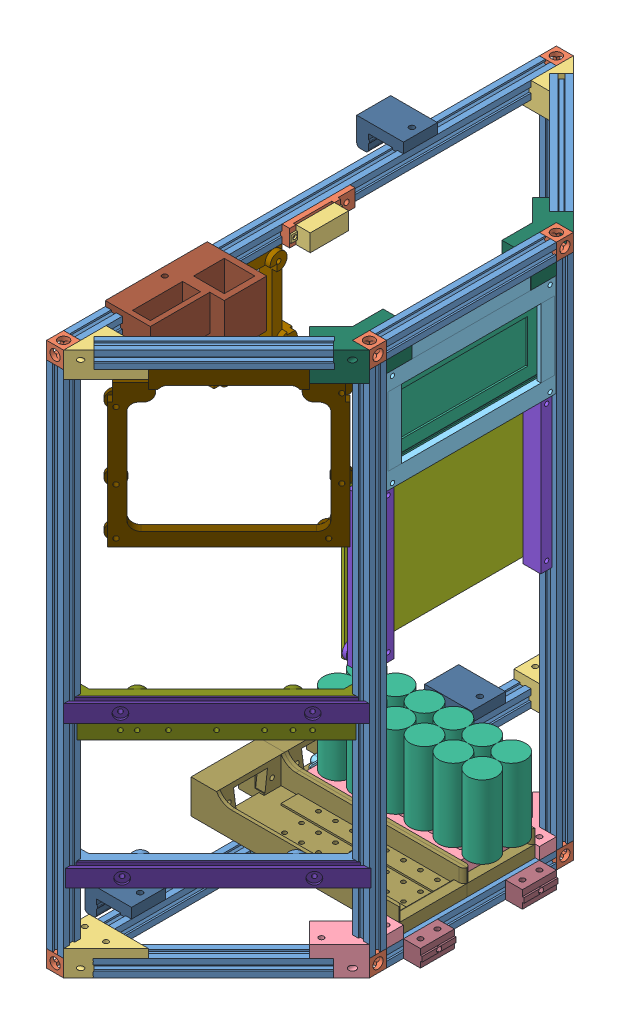
SolidWorks assembly BigRobotElectronicalBlock, configuration Default. Lengths in mm.
Overall size (127.77 326 300).
67 component instances, 24 part files, 141 mates.
Components (placement in the parent):
- Makerbeam50-1000mm-1: Makerbeam50-1000mm [280mm] at (89.8125 150.9684 79.3886) size (10 10 280)
- MakerBeam-cube-1: MakerBeam-cube [Default] at (89.8125 150.9684 359.3886) x (0 1 0) z (0 0 1) size (10 10 10)
- Makerbeam50-1000mm-2: Makerbeam50-1000mm [300mm] at (89.8125 145.9684 364.3886) x (0 0 1) z (0 -1 0) size (10 10 300)
- MakerBeam-cube-2: MakerBeam-cube [Default] at (94.8125 -159.0316 364.3886) x (0 -1 0) z (-1 0 0) size (10 10 10)
- Makerbeam50-1000mm-3: Makerbeam50-1000mm [280mm] at (89.8125 -159.0316 79.3886) size (10 10 280)
- ElectronicalMakerBeamBottomFix45-1: ElectronicalMakerBeamBottomFix45 [Right] at (94.8125 -164.0316 69.3886) x (0 0 -1) z (0 1 0) size (25 35 15)
- Makerbeam50-1000mm-5: Makerbeam50-1000mm [300mm] at (89.8125 145.9684 74.3886) x (0 0 -1) z (0 -1 0) size (10 10 300)
- MakerBeam-cube-3: MakerBeam-cube [Default] at (94.8125 -159.0316 74.3886) x (0 0 -1) z (-1 0 0) size (10 10 10)
- Makerbeam50-1000mm-6: Makerbeam50-1000mm [100mm] at (100.2145 -159.0316 81.8617) x (0.707107 0 -0.707107) z (0.707107 0 0.707107) size (10 10 100)
- MakerBeam-cube-4: MakerBeam-cube [Default] at (89.8125 150.9684 79.3886) x (-1 0 0) z (0 0 -1) size (10 10 10)
- ElectronicalMakerBeamBottomFix135-1: ElectronicalMakerBeamBottomFix135 [Right] at (94.8125 -164.0316 69.3886) x (0 0 -1) z (0 1 0) size (37.68 29.7 17)
- Makerbeam50-1000mm-7: Makerbeam50-1000mm [100mm] at (179.8125 -159.0316 169.3886) size (10 10 100)
- Makerbeam50-1000mm-8: Makerbeam50-1000mm [300mm] at (179.8125 -154.0316 164.3886) x (0 0 1) z (0 1 0) size (10 10 300)
- MakerBeam-cube-5: MakerBeam-cube [Default] at (174.8125 -159.0316 164.3886) x (0 -1 0) z (1 0 0) size (10 10 10)
- ElectronicalMakerBeamBottomFix45-2: ElectronicalMakerBeamBottomFix45 [Left] at (94.8125 155.9684 129.3886) x (0 0 1) z (0 -1 0) size (25 35 15)
- Makerbeam50-1000mm-9: Makerbeam50-1000mm [100mm] at (100.2145 150.9684 81.8617) x (0.707107 0 -0.707107) z (0.707107 0 0.707107) size (10 10 100)
- MakerBeam-cube-6: MakerBeam-cube [Default] at (179.8125 145.9684 164.3886) x (1 0 0) z (0 1 0) size (10 10 10)
- Makerbeam50-1000mm-10: Makerbeam50-1000mm [100mm] at (179.8125 150.9684 169.3886) size (10 10 100)
- MakerBeam-cube-7: MakerBeam-cube [Default] at (179.8125 150.9684 269.3886) size (10 10 10)
- Makerbeam50-1000mm-11: Makerbeam50-1000mm [300mm] at (179.8125 145.9684 274.3886) x (1 0 0) z (0 -1 0) size (10 10 300)
- MakerBeam-cube-8: MakerBeam-cube [Default] at (179.8125 -159.0316 269.3886) x (0 -1 0) z (0 0 1) size (10 10 10)
- ElectronicalMakerBeamBottomFix135-3: ElectronicalMakerBeamBottomFix135 [Left] at (204.8125 -164.0316 369.3886) x (0 0 1) z (0 1 0) size (37.68 29.7 17)
- Makerbeam50-1000mm-12: Makerbeam50-1000mm [100mm] at (170.6704 -159.0316 286.4597) x (0.707107 0 0.707107) z (-0.707107 0 0.707107) size (10 10 100)
- Makerbeam50-1000mm-13: Makerbeam50-1000mm [100mm] at (170.9252 150.9684 286.2049) x (0.707107 0 0.707107) z (-0.707107 0 0.707107) size (10 10 100)
- ElectronicalMakerBeamBottomFix45-3: ElectronicalMakerBeamBottomFix45 [Right] at (94.8125 155.9684 369.3886) x (0 0 1) z (0 -1 0) size (25 35 15)
- ElectronicalMakerBeamBottomFix45-4: ElectronicalMakerBeamBottomFix45 [Left] at (94.8125 -164.0316 309.3886) x (0 0 -1) z (0 1 0) size (25 35 15)
- 20X4LCD_SupportForBigRobot-1: 20X4LCD_SupportForBigRobot [Default] at (184.8125 78.9684 219.4386) x (-1 0 0) z (0 0 -1) size (12 69 103.9)
- 20X4LCD JHD204A-1: 20X4LCD JHD204A [Default] at (172.8125 108.7157 219.3402) x (0 -0.000058 -1) z (0 -1 0.000058) size (98 9.76 60)
- MotorBoard32_BigRobot_WithSupport-1: MotorBoard32_BigRobot_WithSupport [Default] at (277.5716 44.6572 296.8003) x (0 1 0) z (-1 0 0) size (90 121.5 15)
  - MotorBoard32-1: MotorBoard32 [Défaut] at (-10.6888 77.5617 108.2591) size (88 118.5 2)
  - MotorBoardElectronicalSupportForBigRobot-1: MotorBoardElectronicalSupportForBigRobot [Left] at (34.3112 27.4117 132.2591) x (0 1 0) z (-1 0 0) size (17.6 13 90)
  - MotorBoardElectronicalSupportForBigRobot-2: MotorBoardElectronicalSupportForBigRobot [Right] at (34.3112 127.7117 95.2591) x (0 -1 0) z (-1 0 0) size (17.6 13 90)
- UsbBoardSupport-1: UsbBoardSupport [Défaut] at (87.3125 118.9684 257.8488) x (0 -1 0) z (1 0 0) size (55 46 10.5)
- ElectronicalToMechanicalTopFixation-1: ElectronicalToMechanicalTopFixation [Default] at (81.0625 155.9684 159.3886) x (0 0 -1) z (0 1 0) size (20 27.5 16)
- PowerSwitchSupport-1: PowerSwitchSupport [Default] at (102.3125 158.9684 304.8488) x (0 0 1) z (0 -1 0) size (60 35 28)
- BatteriesBottomRackSmallRobot-1: BatteriesBottomRackSmallRobot [Default] at (121.0625 -154.0316 199.3886) x (0 0 -1) z (1 0 0) size (40 20 122.5)
- BigRobot-ElectronicalBlock-BatteriesRackSmallSupport-1: BigRobot-ElectronicalBlock-BatteriesRackSmallSupport [Default] at (164.8125 -164.0316 179.3886) x (-1 0 0) z (0 0 1) size (31 10 20)
- BigRobot-ElectronicalBlock-BatteriesRackBigSupport-1: BigRobot-ElectronicalBlock-BatteriesRackBigSupport [Default] at (104.8125 -164.0316 259.3886) x (1 0 0) z (0 0 -1) size (11 10 80)
- ElectronicalMakerBeamTopFix135-1: ElectronicalMakerBeamTopFix135 [Left] at (204.8125 155.9684 69.3886) x (0 0 -1) z (0 -1 0) size (42.68 29.7 17)
- ElectronicalMakerBeamTopFix135-2: ElectronicalMakerBeamTopFix135 [Right] at (94.8125 155.9684 369.3886) x (0 0 1) z (0 -1 0) size (42.68 29.7 17)
- BatteriesBottomRackSmallRobot-2: BatteriesBottomRackSmallRobot [Default] at (121.0625 -154.0316 239.3886) x (0 0 -1) z (1 0 0) size (40 20 122.5)
- BigRobot-ElectronicalBlock-BatteriesRackSmallSupport-2: BigRobot-ElectronicalBlock-BatteriesRackSmallSupport [Default] at (164.8125 -164.0316 239.3886) x (-1 0 0) z (0 0 1) size (31 10 20)
- BigRobotWindowCorner90x90x45degSupport_PowerboardMiddle-1: BigRobotWindowCorner90x90x45degSupport_PowerboardMiddle [Default] at (135.8125 -35.4689 320.3886) x (0 0 -1) z (0 -1 0) size (92 92 22.5)
- BigRobotWindowCorner90x90x45degCover-1: BigRobotWindowCorner90x90x45degCover [Default] at (139.8125 -29.2189 324.3886) x (0 0 -1) z (0 -1 0) size (90 90 10)
- ElectronicalMainBoard-Support-1: ElectronicalMainBoard-Support [Défaut] at (143.4467 98.9684 320.7544) x (0.707107 0 -0.707107) z (-0.707107 0 -0.707107) size (104 95.5 12.5)
- BigRobotWindowCorner90x90x45degSupport-1: BigRobotWindowCorner90x90x45degSupport [Default] at (136.3125 -113.1971 319.8886) x (0 0 -1) z (0 -1 0) size (93 93 10)
- BigRobotWindowCorner90x90x45degCover-2: BigRobotWindowCorner90x90x45degCover [Default] at (140.3125 -113.1971 323.8886) x (0 0 -1) z (0 -1 0) size (90 90 10)
- ElectronicalToMechanicalTopFixation-2: ElectronicalToMechanicalTopFixation [Default] at (81.0625 -154.0316 119.3886) x (0 0 -1) z (0 1 0) size (20 27.5 16)
- ElectronicalToMechanicalTopFixation-3: ElectronicalToMechanicalTopFixation [Default] at (81.0625 -154.0316 319.3886) x (0 0 -1) z (0 1 0) size (20 27.5 16)
- LCD_MiniVoltmeterSupport-1: LCD_MiniVoltmeterSupport [Default] at (97.8125 145.9684 200.8488) x (0 0 1) z (-1 0 0) size (40 10 5.5)
- LCD_MiniVoltmeter-1: LCD_MiniVoltmeter [Default] at (99.3125 150.9684 225.8488) x (0 0 -1) z (1 0 0) size (30.25 10.15 8.4)
- Battery-With-Support_Assembly-1: Battery-With-Support_Assembly [Default] at (202.4217 -184.624 172.3178) x (0 0 1) z (-1 0 0) size (35.62 54.25 108.57)
  - BatteriesBottomSupportComplete-1: BatteriesBottomSupportComplete [Default] at (27.3209 40.5925 25.7492) size (35.5 35 91)
  - DSub-25-Harting-1: DSub-25-Harting [По умолчанию] at (27.3159 40.5925 116.7492) size (30.8 12.5 18.9)
  - Battery-Pack2x6-1: Battery-Pack2x6 [Défaut] at (29.2673 24.0925 94.2205) x (1 0 0) z (0 1 0) size (34 102 43)
    - Batterie-Element-1: Batterie-Element [Défaut] at (5.6828 -14.1168 21.5) size (17 17 43)
    - Batterie-Element-2: Batterie-Element [Défaut] at (-11.3172 -14.1168 21.5) size (17 17 43)
    - Batterie-Element-3: Batterie-Element [Défaut] at (5.6828 2.8832 21.5) size (17 17 43)
    - Batterie-Element-4: Batterie-Element [Défaut] at (5.6828 19.8832 21.5) size (17 17 43)
    - Batterie-Element-5: Batterie-Element [Défaut] at (5.6828 36.8832 21.5) size (17 17 43)
    - Batterie-Element-6: Batterie-Element [Défaut] at (5.6828 53.8832 21.5) size (17 17 43)
    - Batterie-Element-7: Batterie-Element [Défaut] at (5.6828 70.8832 21.5) size (17 17 43)
    - Batterie-Element-8: Batterie-Element [Défaut] at (-11.3172 2.8832 21.5) size (17 17 43)
    - Batterie-Element-9: Batterie-Element [Défaut] at (-11.3172 19.8832 21.5) size (17 17 43)
    - Batterie-Element-10: Batterie-Element [Défaut] at (-11.3172 36.8832 21.5) size (17 17 43)
    - Batterie-Element-11: Batterie-Element [Défaut] at (-11.3172 53.8832 21.5) size (17 17 43)
    - Batterie-Element-12: Batterie-Element [Défaut] at (-11.3172 70.8832 21.5) size (17 17 43)
Mates (geometry in assembly coordinates):
- Concentric1: concentric anti-aligned: cylinder of Makerbeam50-1000mm-1 through (89.8125 150.9684 359.3886) axis (0 0 -1) radius 1.25; cylinder of MakerBeam-cube-1 through (89.8125 150.9684 369.3886) axis (0 0 1) radius 1.25
- Coincident1: coincident aligned: plane of Makerbeam50-1000mm-1 through (94.8125 155.9684 359.3886) normal (1 0 0); plane of MakerBeam-cube-1 through (94.8125 155.9684 369.3886) normal (1 0 0)
- Coincident2: coincident anti-aligned: plane of Makerbeam50-1000mm-1 through (89.8125 150.9684 359.3886) normal (0 0 1); plane of MakerBeam-cube-1 through (89.8125 150.9684 359.3886) normal (0 0 -1)
- Concentric2: concentric aligned: cylinder of MakerBeam-cube-1 through (89.8125 155.9684 364.3886) axis (0 1 0) radius 1.25; cylinder of Makerbeam50-1000mm-2 through (89.8125 -154.0316 364.3886) axis (0 1 0) radius 1.25
- Coincident3: coincident aligned: plane of MakerBeam-cube-1 through (89.8125 150.9684 369.3886) normal (0 0 1); plane of Makerbeam50-1000mm-2 through (84.8125 -154.0316 369.3886) normal (0 0 1)
- Coincident4: coincident anti-aligned: plane of MakerBeam-cube-1 through (94.8125 145.9684 369.3886) normal (0 -1 0); plane of Makerbeam50-1000mm-2 through (89.8125 145.9684 364.3886) normal (0 1 0)
- Concentric3: concentric anti-aligned: cylinder of Makerbeam50-1000mm-2 through (89.8125 -154.0316 364.3886) axis (0 1 0) radius 1.25; cylinder of MakerBeam-cube-2 through (89.8125 -164.0316 364.3886) axis (0 -1 0) radius 1.25
- Coincident5: coincident aligned: plane of Makerbeam50-1000mm-2 through (84.8125 -154.0316 369.3886) normal (0 0 1); plane of MakerBeam-cube-2 through (84.8125 -164.0316 369.3886) normal (0 0 1)
- Coincident6: coincident anti-aligned: plane of Makerbeam50-1000mm-2 through (89.8125 -154.0316 364.3886) normal (0 -1 0); plane of MakerBeam-cube-2 through (84.8125 -154.0316 359.3886) normal (0 1 0)
- Concentric4: concentric aligned: cylinder of MakerBeam-cube-2 through (89.8125 -159.0316 359.3886) axis (0 0 -1) radius 1.25; cylinder of Makerbeam50-1000mm-3 through (89.8125 -159.0316 359.3886) axis (0 0 -1) radius 1.25
- Coincident7: coincident aligned: plane of MakerBeam-cube-2 through (94.8125 -159.0316 364.3886) normal (1 0 0); plane of Makerbeam50-1000mm-3 through (94.8125 -160.5316 359.3886) normal (1 0 0)
- Coincident8: coincident anti-aligned: plane of MakerBeam-cube-2 through (84.8125 -164.0316 359.3886) normal (0 0 -1); plane of Makerbeam50-1000mm-3 through (89.8125 -159.0316 359.3886) normal (0 0 1)
- Coincident9: coincident anti-aligned: plane of Makerbeam50-1000mm-3 through (84.8125 -154.0316 359.3886) normal (0 1 0); plane of ElectronicalMakerBeamBottomFix45-1 through (94.8125 -154.0316 69.3886) normal (0 -1 0)
- Coincident10: coincident aligned: plane of Makerbeam50-1000mm-3 through (89.8125 -159.0316 79.3886) normal (0 0 -1); plane of ElectronicalMakerBeamBottomFix45-1 through (94.8125 -149.0316 79.3886) normal (0 0 -1)
- Coincident11: coincident aligned: plane of Makerbeam50-1000mm-3 through (84.8125 -157.5316 359.3886) normal (-1 0 0); plane of ElectronicalMakerBeamBottomFix45-1 through (84.8125 -149.0316 79.3886) normal (-1 0 0)
- Coincident13: coincident anti-aligned: plane of ElectronicalMakerBeamBottomFix45-1 through (94.8125 -149.0316 69.3886) normal (-1 0 0); plane of Makerbeam50-1000mm-5 through (94.8125 -154.0316 72.8886) normal (1 0 0)
- Concentric5: concentric aligned: cylinder of Makerbeam50-1000mm-3 through (89.8125 -159.0316 359.3886) axis (0 0 -1) radius 1.25; cylinder of MakerBeam-cube-3 through (89.8125 -159.0316 69.3886) axis (0 0 -1) radius 1.25
- Coincident14: coincident anti-aligned: plane of ElectronicalMakerBeamBottomFix45-1 through (94.8125 -149.0316 69.3886) normal (-1 0 0); plane of MakerBeam-cube-3 through (94.8125 -159.0316 74.3886) normal (1 0 0)
- Coincident15: coincident anti-aligned: plane of Makerbeam50-1000mm-3 through (89.8125 -159.0316 79.3886) normal (0 0 -1); plane of MakerBeam-cube-3 through (84.8125 -154.0316 79.3886) normal (0 0 1)
- Coincident16: coincident anti-aligned: plane of Makerbeam50-1000mm-5 through (89.8125 -154.0316 74.3886) normal (0 -1 0); plane of MakerBeam-cube-3 through (84.8125 -154.0316 69.3886) normal (0 1 0)
- Concentric6: concentric aligned: cylinder of Makerbeam50-1000mm-5 through (89.8125 -154.0316 74.3886) axis (0 1 0) radius 1.25; cylinder of MakerBeam-cube-3 through (89.8125 -154.0316 74.3886) axis (0 1 0) radius 1.25
- Coincident18: coincident anti-aligned: plane of ElectronicalMakerBeamBottomFix45-1 through (96.679 -149.0316 85.3973) normal (0.707107 0 -0.707107); plane of Makerbeam50-1000mm-6 through (167.3897 -157.5316 156.1079) normal (-0.707107 0 0.707107)
- Coincident19: coincident aligned: plane of ElectronicalMakerBeamBottomFix45-1 through (94.8125 -164.0316 69.3886) normal (0 -1 0); plane of Makerbeam50-1000mm-6 through (171.9858 -164.0316 151.5118) normal (0 -1 0)
- Coincident20: coincident anti-aligned: plane of ElectronicalMakerBeamBottomFix45-1 through (103.75 -149.0316 78.3262) normal (0.707107 0 0.707107); plane of Makerbeam50-1000mm-6 through (100.2145 -159.0316 81.8617) normal (-0.707107 0 -0.707107)
- Concentric7: concentric aligned: cylinder of Makerbeam50-1000mm-1 through (89.8125 150.9684 359.3886) axis (0 0 -1) radius 1.25; cylinder of MakerBeam-cube-4 through (89.8125 150.9684 69.3886) axis (0 0 -1) radius 1.25
- Coincident22: coincident aligned: plane of Makerbeam50-1000mm-1 through (94.8125 155.9684 359.3886) normal (1 0 0); plane of MakerBeam-cube-4 through (94.8125 145.9684 69.3886) normal (1 0 0)
- Coincident23: coincident anti-aligned: plane of Makerbeam50-1000mm-1 through (89.8125 150.9684 79.3886) normal (0 0 -1); plane of MakerBeam-cube-4 through (89.8125 150.9684 79.3886) normal (0 0 1)
- Coincident25: coincident aligned: plane of Makerbeam50-1000mm-6 through (171.9858 -164.0316 151.5118) normal (0 -1 0); plane of ElectronicalMakerBeamBottomFix135-1 through (94.8125 -164.0316 69.3886) normal (0 -1 0)
- Parallel1: parallel anti-aligned: plane of Makerbeam50-1000mm-6 through (170.9252 -159.0316 152.5724) normal (0.707107 0 0.707107); plane of ElectronicalMakerBeamBottomFix135-1 through (174.2059 -164.0316 148.782) normal (-0.707107 0 -0.707107)
- Coincident27: coincident aligned: plane of Makerbeam50-1000mm-6 through (174.4607 -154.0316 149.0369) normal (0.707107 0 -0.707107); plane of ElectronicalMakerBeamBottomFix135-1 through (184.8125 -147.0316 159.3886) normal (0.707107 0 -0.707107)
- Distance2: distance = 80 mm aligned: plane of ElectronicalMakerBeamBottomFix135-1 through (174.8125 -147.0316 159.3886) normal (1 0 0); plane of Makerbeam50-1000mm-3 through (94.8125 -154.0316 359.3886) normal (1 0 0)
- Coincident30: coincident aligned: plane of ElectronicalMakerBeamBottomFix135-1 through (94.8125 -164.0316 169.3886) normal (0 0 -1); plane of Makerbeam50-1000mm-7 through (179.8125 -159.0316 169.3886) normal (0 0 -1)
- Coincident32: coincident aligned: plane of ElectronicalMakerBeamBottomFix135-1 through (184.8125 -147.0316 169.3886) normal (1 0 0); plane of Makerbeam50-1000mm-7 through (184.8125 -154.0316 269.3886) normal (1 0 0)
- Coincident33: coincident aligned: plane of ElectronicalMakerBeamBottomFix135-1 through (94.8125 -164.0316 69.3886) normal (0 -1 0); plane of Makerbeam50-1000mm-7 through (178.3125 -164.0316 269.3886) normal (0 -1 0)
- Coincident34: coincident anti-aligned: plane of ElectronicalMakerBeamBottomFix135-1 through (94.8125 -164.0316 169.3886) normal (0 0 -1); plane of Makerbeam50-1000mm-8 through (184.8125 145.9684 169.3886) normal (0 0 1)
- Coincident35: coincident aligned: plane of Makerbeam50-1000mm-7 through (184.8125 -154.0316 269.3886) normal (1 0 0); plane of Makerbeam50-1000mm-8 through (184.8125 145.9684 165.8886) normal (1 0 0)
- Concentric8: concentric anti-aligned: cylinder of Makerbeam50-1000mm-7 through (179.8125 -159.0316 269.3886) axis (0 0 -1) radius 1.25; cylinder of MakerBeam-cube-5 through (179.8125 -159.0316 169.3886) axis (0 0 1) radius 1.25
- Concentric9: concentric aligned: cylinder of Makerbeam50-1000mm-8 through (179.8125 145.9684 164.3886) axis (0 -1 0) radius 1.25; cylinder of MakerBeam-cube-5 through (179.8125 -164.0316 164.3886) axis (0 -1 0) radius 1.25
- Coincident36: coincident anti-aligned: plane of Makerbeam50-1000mm-8 through (179.8125 -154.0316 164.3886) normal (0 -1 0); plane of MakerBeam-cube-5 through (184.8125 -154.0316 169.3886) normal (0 1 0)
- Coincident38: coincident aligned: plane of Makerbeam50-1000mm-1 through (91.3125 155.9684 359.3886) normal (0 1 0); plane of ElectronicalMakerBeamBottomFix45-2 through (94.8125 155.9684 69.3886) normal (0 1 0)
- Coincident39: coincident anti-aligned: plane of Makerbeam50-1000mm-1 through (94.8125 155.9684 359.3886) normal (1 0 0); plane of ElectronicalMakerBeamBottomFix45-2 through (94.8125 140.9684 69.3886) normal (-1 0 0)
- Coincident40: coincident anti-aligned: line of MakerBeam-cube-4 through (94.8125 155.9684 69.3886) axis (0 -1 0); line of ElectronicalMakerBeamBottomFix45-2 through (94.8125 140.9684 69.3886) axis (0 1 0)
- Coincident41: coincident aligned: plane of ElectronicalMakerBeamBottomFix45-2 through (94.8125 155.9684 69.3886) normal (0 1 0); plane of Makerbeam50-1000mm-9 through (167.3897 155.9684 156.1079) normal (0 1 0)
- Coincident42: coincident anti-aligned: plane of ElectronicalMakerBeamBottomFix45-2 through (103.75 140.9684 78.3262) normal (0.707107 0 0.707107); plane of Makerbeam50-1000mm-9 through (100.2145 150.9684 81.8617) normal (-0.707107 0 -0.707107)
- Coincident43: coincident anti-aligned: plane of ElectronicalMakerBeamBottomFix45-2 through (96.679 140.9684 85.3973) normal (0.707107 0 -0.707107); plane of Makerbeam50-1000mm-9 through (167.3897 145.9684 156.1079) normal (-0.707107 0 0.707107)
- Concentric10: concentric anti-aligned: cylinder of Makerbeam50-1000mm-8 through (179.8125 145.9684 164.3886) axis (0 -1 0) radius 1.25; cylinder of MakerBeam-cube-6 through (179.8125 155.9684 164.3886) axis (0 1 0) radius 1.25
- Coincident47: coincident aligned: plane of Makerbeam50-1000mm-8 through (184.8125 145.9684 165.8886) normal (1 0 0); plane of MakerBeam-cube-6 through (184.8125 155.9684 169.3886) normal (1 0 0)
- Coincident48: coincident anti-aligned: plane of Makerbeam50-1000mm-8 through (179.8125 145.9684 164.3886) normal (0 1 0); plane of MakerBeam-cube-6 through (179.8125 145.9684 164.3886) normal (0 -1 0)
- Coincident51: coincident anti-aligned: plane of MakerBeam-cube-6 through (184.8125 155.9684 169.3886) normal (0 0 1); plane of Makerbeam50-1000mm-10 through (179.8125 150.9684 169.3886) normal (0 0 -1)
- Concentric11: concentric anti-aligned: cylinder of Makerbeam50-1000mm-10 through (179.8125 150.9684 269.3886) axis (0 0 -1) radius 1.25; cylinder of MakerBeam-cube-7 through (179.8125 150.9684 279.3886) axis (0 0 1) radius 1.25
- Coincident52: coincident aligned: plane of Makerbeam50-1000mm-10 through (184.8125 149.4684 269.3886) normal (1 0 0); plane of MakerBeam-cube-7 through (184.8125 145.9684 279.3886) normal (1 0 0)
- Coincident53: coincident anti-aligned: plane of Makerbeam50-1000mm-10 through (179.8125 150.9684 269.3886) normal (0 0 1); plane of MakerBeam-cube-7 through (179.8125 150.9684 269.3886) normal (0 0 -1)
- Concentric12: concentric anti-aligned: cylinder of MakerBeam-cube-7 through (179.8125 145.9684 274.3886) axis (0 -1 0) radius 1.25; cylinder of Makerbeam50-1000mm-11 through (179.8125 -154.0316 274.3886) axis (0 1 0) radius 1.25
- Coincident54: coincident anti-aligned: plane of MakerBeam-cube-7 through (184.8125 145.9684 279.3886) normal (0 -1 0); plane of Makerbeam50-1000mm-11 through (179.8125 145.9684 274.3886) normal (0 1 0)
- Coincident55: coincident aligned: plane of MakerBeam-cube-7 through (184.8125 145.9684 279.3886) normal (1 0 0); plane of Makerbeam50-1000mm-11 through (184.8125 -154.0316 279.3886) normal (1 0 0)
- Coincident56: coincident anti-aligned: plane of Makerbeam50-1000mm-7 through (179.8125 -159.0316 269.3886) normal (0 0 1); plane of MakerBeam-cube-8 through (179.8125 -159.0316 269.3886) normal (0 0 -1)
- Coincident57: coincident anti-aligned: plane of Makerbeam50-1000mm-11 through (179.8125 -154.0316 274.3886) normal (0 -1 0); plane of MakerBeam-cube-8 through (174.8125 -154.0316 279.3886) normal (0 1 0)
- Coincident58: coincident aligned: plane of Makerbeam50-1000mm-7 through (184.8125 -160.5316 269.3886) normal (1 0 0); plane of MakerBeam-cube-8 through (184.8125 -164.0316 279.3886) normal (1 0 0)
- Coincident59: coincident anti-aligned: plane of Makerbeam50-1000mm-7 through (174.8125 -157.5316 269.3886) normal (-1 0 0); plane of ElectronicalMakerBeamBottomFix135-3 through (174.8125 -147.0316 279.3886) normal (1 0 0)
- Coincident60: coincident aligned: plane of Makerbeam50-1000mm-7 through (178.3125 -164.0316 269.3886) normal (0 -1 0); plane of ElectronicalMakerBeamBottomFix135-3 through (94.8125 -164.0316 369.3886) normal (0 -1 0)
- Coincident61: coincident anti-aligned: plane of MakerBeam-cube-8 through (179.8125 -159.0316 279.3886) normal (0 0 1); plane of ElectronicalMakerBeamBottomFix135-3 through (184.8125 -147.0316 279.3886) normal (0 0 -1)
- Coincident62: coincident aligned: plane of ElectronicalMakerBeamBottomFix135-3 through (184.8125 -147.0316 279.3886) normal (0.707107 0 0.707107); plane of Makerbeam50-1000mm-12 through (103.4952 -154.0316 360.7059) normal (0.707107 0 0.707107)
- Coincident63: coincident aligned: plane of ElectronicalMakerBeamBottomFix135-3 through (94.8125 -164.0316 369.3886) normal (0 -1 0); plane of Makerbeam50-1000mm-12 through (101.0203 -164.0316 358.2311) normal (0 -1 0)
- Coincident64: coincident anti-aligned: plane of ElectronicalMakerBeamBottomFix135-3 through (174.2059 -164.0316 289.9952) normal (-0.707107 0 0.707107); plane of Makerbeam50-1000mm-12 through (170.6704 -159.0316 286.4597) normal (0.707107 0 -0.707107)
- Coincident71: coincident aligned: plane of Makerbeam50-1000mm-13 through (96.679 155.9684 353.38) normal (0 1 0); plane of ElectronicalMakerBeamBottomFix45-3 through (94.8125 155.9684 369.3886) normal (0 1 0)
- Coincident72: coincident aligned: plane of Makerbeam50-1000mm-1 through (84.8125 152.4684 359.3886) normal (-1 0 0); plane of ElectronicalMakerBeamBottomFix45-3 through (84.8125 140.9684 359.3886) normal (-1 0 0)
- Coincident73: coincident aligned: plane of Makerbeam50-1000mm-13 through (103.75 149.4684 360.4511) normal (0.707107 0 0.707107); plane of ElectronicalMakerBeamBottomFix45-3 through (94.8125 140.9684 369.3886) normal (0.707107 0 0.707107)
- Coincident76: coincident aligned: plane of Makerbeam50-1000mm-12 through (103.4952 -154.0316 360.7059) normal (0.707107 0 0.707107); plane of ElectronicalMakerBeamBottomFix45-4 through (94.8125 -149.0316 369.3886) normal (0.707107 0 0.707107)
- Coincident77: coincident aligned: plane of Makerbeam50-1000mm-12 through (101.0203 -164.0316 358.2311) normal (0 -1 0); plane of ElectronicalMakerBeamBottomFix45-4 through (94.8125 -164.0316 369.3886) normal (0 -1 0)
- Coincident78: coincident anti-aligned: plane of MakerBeam-cube-2 through (94.8125 -159.0316 364.3886) normal (1 0 0); plane of ElectronicalMakerBeamBottomFix45-4 through (94.8125 -149.0316 369.3886) normal (-1 0 0)
- Coincident79: coincident anti-aligned: plane of Makerbeam50-1000mm-10 through (181.3125 145.9684 269.3886) normal (0 -1 0); plane of 20X4LCD_SupportForBigRobot-1 through (174.8125 145.9684 254.3886) normal (0 1 0)
- Coincident82: coincident aligned: plane of Makerbeam50-1000mm-10 through (184.8125 149.4684 269.3886) normal (1 0 0); plane of 20X4LCD_SupportForBigRobot-1 through (184.8125 78.9684 219.4386) normal (1 0 0)
- Coincident83: coincident anti-aligned: plane of Makerbeam50-1000mm-11 through (181.3125 -154.0316 269.3886) normal (0 0 -1); plane of 20X4LCD_SupportForBigRobot-1 through (184.8125 78.9684 269.3886) normal (0 0 1)
- Concentric13: concentric anti-aligned: cylinder of 20X4LCD_SupportForBigRobot-1 through (184.8125 136.0684 265.8386) axis (-1 0 0) radius 1.25; circle of 20X4LCD JHD204A-1
- Coincident84: coincident anti-aligned: plane of 20X4LCD_SupportForBigRobot-1 through (172.8125 138.9684 169.4886) normal (-1 0 0); plane of 20X4LCD JHD204A-1 through (172.8125 78.7129 170.492) normal (1 0 0)
- Coincident85: coincident anti-aligned: plane of Makerbeam50-1000mm-11 through (178.3125 -154.0316 269.3886) normal (0 0 -1); plane of MotorBoard32_BigRobot_WithSupport-1/MotorBoardElectronicalSupportForBigRobot-1 through (174.8125 -11.0316 269.3886) normal (0 0 1)
- Coincident87: coincident anti-aligned: plane of Makerbeam50-1000mm-11 through (174.8125 -154.0316 269.3886) normal (-1 0 0); plane of MotorBoard32_BigRobot_WithSupport-1/MotorBoardElectronicalSupportForBigRobot-1 through (174.8125 -11.0316 279.3886) normal (1 0 0)
- Coincident88: coincident anti-aligned: plane of 20X4LCD_SupportForBigRobot-1 through (172.8125 78.9684 169.4886) normal (0 -1 0); plane of MotorBoard32_BigRobot_WithSupport-1/MotorBoardElectronicalSupportForBigRobot-1 through (182.3125 78.9684 269.3886) normal (0 1 0)
- Coincident89: coincident anti-aligned: plane of Makerbeam50-1000mm-1 through (88.3125 145.9684 359.3886) normal (0 -1 0); plane of UsbBoardSupport-1 through (94.8125 145.9684 280.8488) normal (0 1 0)
- Coincident90: coincident aligned: plane of Makerbeam50-1000mm-1 through (94.8125 155.9684 359.3886) normal (1 0 0); plane of UsbBoardSupport-1 through (94.8125 118.9684 257.8488) normal (1 0 0)
- Coincident91: coincident anti-aligned: plane of Makerbeam50-1000mm-1 through (84.8125 155.9684 359.3886) normal (0 1 0); plane of ElectronicalToMechanicalTopFixation-1 through (81.0625 155.9684 159.3886) normal (0 -1 0)
- Coincident93: coincident aligned: plane of Makerbeam50-1000mm-1 through (94.8125 155.9684 359.3886) normal (1 0 0); plane of ElectronicalToMechanicalTopFixation-1 through (94.8125 161.9684 169.3886) normal (1 0 0)
- Coincident94: coincident anti-aligned: plane of Makerbeam50-1000mm-1 through (84.8125 155.9684 359.3886) normal (0 1 0); plane of PowerSwitchSupport-1 through (102.3125 155.9684 304.8488) normal (0 -1 0)
- Coincident95: coincident anti-aligned: plane of Makerbeam50-1000mm-1 through (94.8125 155.9684 359.3886) normal (1 0 0); plane of PowerSwitchSupport-1 through (94.8125 135.9684 274.8488) normal (-1 0 0)
- Coincident96: coincident anti-aligned: plane of Makerbeam50-1000mm-7 through (174.8125 -154.0316 269.3886) normal (0 1 0); plane of BatteriesBottomRackSmallRobot-1 through (182.3125 -154.0316 179.3886) normal (0 -1 0)
- Distance3: distance = 2.5 mm aligned: plane of Makerbeam50-1000mm-7 through (184.8125 -154.0316 269.3886) normal (1 0 0); plane of BatteriesBottomRackSmallRobot-1 through (182.3125 -154.0316 199.3886) normal (1 0 0)
- Coincident97: coincident anti-aligned: plane of Makerbeam50-1000mm-7 through (174.8125 -164.0316 269.3886) normal (-1 0 0); plane of BigRobot-ElectronicalBlock-BatteriesRackSmallSupport-1 through (174.8125 -164.0316 199.3886) normal (1 0 0)
- Coincident98: coincident aligned: plane of Makerbeam50-1000mm-7 through (178.3125 -164.0316 269.3886) normal (0 -1 0); plane of BigRobot-ElectronicalBlock-BatteriesRackSmallSupport-1 through (164.8125 -164.0316 199.3886) normal (0 -1 0)
- Parallel3: parallel aligned: cylinder of BatteriesBottomRackSmallRobot-1 through (169.8125 -134.0316 184.3886) axis (0 -1 0) radius 1.25; cylinder of BigRobot-ElectronicalBlock-BatteriesRackSmallSupport-1 through (169.8125 -154.0316 184.3886) axis (0 -1 0) radius 1.5
- Coincident99: coincident aligned: plane of BatteriesBottomRackSmallRobot-1 through (182.3125 -139.0316 179.3886) normal (0 0 -1); plane of BigRobot-ElectronicalBlock-BatteriesRackSmallSupport-1 through (164.8125 -164.0316 179.3886) normal (0 0 -1)
- Coincident100: coincident aligned: plane of Makerbeam50-1000mm-3 through (91.3125 -154.0316 359.3886) normal (0 1 0); plane of BigRobot-ElectronicalBlock-BatteriesRackBigSupport-1 through (94.8125 -154.0316 179.3886) normal (0 1 0)
- Coincident101: coincident anti-aligned: plane of Makerbeam50-1000mm-3 through (94.8125 -154.0316 359.3886) normal (1 0 0); plane of BigRobot-ElectronicalBlock-BatteriesRackBigSupport-1 through (94.8125 -157.5816 179.3886) normal (-1 0 0)
- Coincident102: coincident aligned: plane of BatteriesBottomRackSmallRobot-1 through (182.3125 -139.0316 179.3886) normal (0 0 -1); plane of BigRobot-ElectronicalBlock-BatteriesRackBigSupport-1 through (104.8125 -164.0316 179.3886) normal (0 0 -1)
- Coincident103: coincident anti-aligned: plane of ElectronicalMakerBeamBottomFix135-1 through (174.8125 -147.0316 179.3886) normal (0 0 1); plane of BatteriesBottomRackSmallRobot-1 through (182.3125 -139.0316 179.3886) normal (0 0 -1)
- Coincident104: coincident aligned: plane of MakerBeam-cube-6 through (179.8125 155.9684 164.3886) normal (0 1 0); plane of ElectronicalMakerBeamTopFix135-1 through (94.8125 155.9684 69.3886) normal (0 1 0)
- Coincident105: coincident anti-aligned: plane of MakerBeam-cube-6 through (184.8125 155.9684 159.3886) normal (0 0 -1); plane of ElectronicalMakerBeamTopFix135-1 through (184.8125 138.9684 159.3886) normal (0 0 1)
- Coincident106: coincident anti-aligned: line of MakerBeam-cube-6 through (184.8125 155.9684 159.3886) axis (0 -1 0); line of ElectronicalMakerBeamTopFix135-1 through (184.8125 138.9684 159.3886) axis (0 1 0)
- Coincident107: coincident aligned: plane of MakerBeam-cube-6 through (184.8125 155.9684 169.3886) normal (1 0 0); plane of Makerbeam50-1000mm-10 through (184.8125 155.9684 269.3886) normal (1 0 0)
- Coincident108: coincident aligned: plane of MakerBeam-cube-6 through (179.8125 155.9684 164.3886) normal (0 1 0); plane of Makerbeam50-1000mm-10 through (181.3125 155.9684 269.3886) normal (0 1 0)
- Coincident109: coincident anti-aligned: plane of Makerbeam50-1000mm-13 through (100.2145 150.9684 356.9156) normal (-0.707107 0 0.707107); plane of ElectronicalMakerBeamBottomFix45-3 through (103.75 140.9684 360.4511) normal (0.707107 0 -0.707107)
- Coincident110: coincident aligned: plane of Makerbeam50-1000mm-13 through (96.679 155.9684 353.38) normal (0 1 0); plane of ElectronicalMakerBeamTopFix135-2 through (94.8125 155.9684 369.3886) normal (0 1 0)
- Coincident111: coincident aligned: plane of MakerBeam-cube-1 through (94.8125 155.9684 369.3886) normal (0 1 0); plane of ElectronicalMakerBeamBottomFix45-3 through (94.8125 155.9684 369.3886) normal (0 1 0)
- Coincident112: coincident anti-aligned: line of MakerBeam-cube-7 through (184.8125 155.9684 279.3886) axis (-1 0 0); line of ElectronicalMakerBeamTopFix135-2 through (174.8125 155.9684 279.3886) axis (1 0 0)
- Coincident114: coincident anti-aligned: plane of MakerBeam-cube-7 through (174.8125 145.9684 279.3886) normal (-1 0 0); plane of ElectronicalMakerBeamTopFix135-2 through (174.8125 138.9684 279.3886) normal (1 0 0)
- Coincident115: coincident aligned: line of MakerBeam-cube-1 through (94.8125 145.9684 369.3886) axis (0 1 0); line of ElectronicalMakerBeamBottomFix45-3 through (94.8125 140.9684 369.3886) axis (0 1 0)
- Coincident116: coincident anti-aligned: plane of BatteriesBottomRackSmallRobot-1 through (182.3125 -154.0316 219.3886) normal (0 0 1); plane of BatteriesBottomRackSmallRobot-2 through (182.3125 -139.0316 219.3886) normal (0 0 -1)
- Coincident117: coincident aligned: plane of BatteriesBottomRackSmallRobot-1 through (182.3125 -154.0316 199.3886) normal (1 0 0); plane of BatteriesBottomRackSmallRobot-2 through (182.3125 -154.0316 239.3886) normal (1 0 0)
- Coincident118: coincident aligned: plane of BatteriesBottomRackSmallRobot-1 through (182.3125 -139.0316 219.3886) normal (0 1 0); plane of BatteriesBottomRackSmallRobot-2 through (182.3125 -139.0316 221.3886) normal (0 1 0)
- Coincident119: coincident anti-aligned: plane of Makerbeam50-1000mm-7 through (174.8125 -164.0316 269.3886) normal (-1 0 0); plane of BigRobot-ElectronicalBlock-BatteriesRackSmallSupport-2 through (174.8125 -164.0316 259.3886) normal (1 0 0)
- Coincident120: coincident aligned: plane of Makerbeam50-1000mm-7 through (178.3125 -164.0316 269.3886) normal (0 -1 0); plane of BigRobot-ElectronicalBlock-BatteriesRackSmallSupport-2 through (164.8125 -164.0316 259.3886) normal (0 -1 0)
- Coincident121: coincident anti-aligned: plane of ElectronicalMakerBeamBottomFix135-3 through (174.8125 -147.0316 259.3886) normal (0 0 -1); plane of BigRobot-ElectronicalBlock-BatteriesRackSmallSupport-2 through (164.8125 -164.0316 259.3886) normal (0 0 1)
- Coincident122: coincident anti-aligned: plane of Makerbeam50-1000mm-11 through (174.8125 -154.0316 275.8886) normal (-1 0 0); plane of BigRobotWindowCorner90x90x45degSupport_PowerboardMiddle-1 through (174.8125 -46.7189 279.3886) normal (1 0 0)
- Coincident123: coincident anti-aligned: plane of Makerbeam50-1000mm-11 through (174.8125 -154.0316 279.3886) normal (0 0 1); plane of BigRobotWindowCorner90x90x45degSupport_PowerboardMiddle-1 through (176.8125 -46.7189 279.3886) normal (0 0 -1)
- Coincident124: coincident anti-aligned: plane of BigRobotWindowCorner90x90x45degSupport_PowerboardMiddle-1 through (94.8125 -46.7189 361.3886) normal (0.707107 0 0.707107); plane of BigRobotWindowCorner90x90x45degCover-1 through (94.8125 -34.2189 361.3886) normal (-0.707107 0 -0.707107)
- Concentric15: concentric aligned: cylinder of BigRobotWindowCorner90x90x45degSupport_PowerboardMiddle-1 through (205.0968 -29.2189 333.1044) axis (-0.707107 0 -0.707107) radius 1.25; cylinder of BigRobotWindowCorner90x90x45degCover-1 through (167.6323 -29.2189 295.6399) axis (-0.707107 0 -0.707107) radius 1.25
- Concentric16: concentric aligned: cylinder of BigRobotWindowCorner90x90x45degSupport_PowerboardMiddle-1 through (148.5282 -29.2189 389.6729) axis (-0.707107 0 -0.707107) radius 1.25; cylinder of BigRobotWindowCorner90x90x45degCover-1 through (111.0638 -29.2189 352.2085) axis (-0.707107 0 -0.707107) radius 1.25
- Coincident125: coincident anti-aligned: plane of UsbBoardSupport-1 through (87.3125 118.9684 274.8488) normal (0 0 1); plane of PowerSwitchSupport-1 through (84.8125 155.9684 274.8488) normal (0 0 -1)
- Coincident126: coincident aligned: plane of Makerbeam50-1000mm-13 through (103.75 149.4684 360.4511) normal (0.707107 0 0.707107); plane of ElectronicalMainBoard-Support-1 through (143.4467 98.9684 320.7544) normal (0.707107 0 0.707107)
- Coincident127: coincident anti-aligned: plane of Makerbeam50-1000mm-13 through (101.2752 145.9684 357.9762) normal (0 -1 0); plane of ElectronicalMainBoard-Support-1 through (100.6668 145.9684 349.3922) normal (0 1 0)
- Coincident128: coincident anti-aligned: plane of ElectronicalMakerBeamTopFix135-2 through (155.114 138.9684 285.0455) normal (-0.707107 0 0.707107); plane of ElectronicalMainBoard-Support-1 through (167.1348 145.9684 297.0663) normal (0.707107 0 -0.707107)
- Coincident129: coincident anti-aligned: plane of Makerbeam50-1000mm-2 through (94.8125 -154.0316 359.3886) normal (0 0 -1); plane of BigRobotWindowCorner90x90x45degSupport-1 through (94.8125 -118.1971 359.3886) normal (0 0 1)
- Coincident130: coincident anti-aligned: plane of Makerbeam50-1000mm-2 through (94.8125 -154.0316 362.8886) normal (1 0 0); plane of BigRobotWindowCorner90x90x45degSupport-1 through (94.8125 -118.1971 361.3886) normal (-1 0 0)
- Coincident131: coincident anti-aligned: plane of BigRobotWindowCorner90x90x45degSupport-1 through (94.8125 -118.1971 361.3886) normal (0.707107 0 0.707107); plane of BigRobotWindowCorner90x90x45degCover-2 through (95.3125 -118.1971 360.8886) normal (-0.707107 0 -0.707107)
- Concentric18: concentric aligned: cylinder of BigRobotWindowCorner90x90x45degSupport-1 through (206.0968 -113.1971 333.1044) axis (-0.707107 0 -0.707107) radius 1.25; cylinder of BigRobotWindowCorner90x90x45degCover-2 through (168.1323 -113.1971 295.1399) axis (-0.707107 0 -0.707107) radius 1.25
- Concentric19: concentric aligned: cylinder of BigRobotWindowCorner90x90x45degSupport-1 through (149.5282 -113.1971 389.6729) axis (-0.707107 0 -0.707107) radius 1.25; cylinder of BigRobotWindowCorner90x90x45degCover-2 through (111.5638 -113.1971 351.7085) axis (-0.707107 0 -0.707107) radius 1.25
- Coincident132: coincident anti-aligned: plane of Makerbeam50-1000mm-3 through (84.8125 -154.0316 359.3886) normal (0 1 0); plane of ElectronicalToMechanicalTopFixation-2 through (81.0625 -154.0316 119.3886) normal (0 -1 0)
- Coincident133: coincident aligned: plane of Makerbeam50-1000mm-3 through (94.8125 -160.5316 359.3886) normal (1 0 0); plane of ElectronicalToMechanicalTopFixation-2 through (94.8125 -148.0316 129.3886) normal (1 0 0)
- Coincident134: coincident anti-aligned: plane of Makerbeam50-1000mm-3 through (91.3125 -154.0316 359.3886) normal (0 1 0); plane of ElectronicalToMechanicalTopFixation-3 through (81.0625 -154.0316 319.3886) normal (0 -1 0)
- Coincident135: coincident aligned: plane of Makerbeam50-1000mm-3 through (94.8125 -154.0316 359.3886) normal (1 0 0); plane of ElectronicalToMechanicalTopFixation-3 through (94.8125 -148.0316 329.3886) normal (1 0 0)
- Distance4: distance = 40 mm aligned: plane of MakerBeam-cube-2 through (84.8125 -164.0316 369.3886) normal (0 0 1); plane of ElectronicalToMechanicalTopFixation-3 through (67.3125 -148.0316 329.3886) normal (0 0 1)
- Distance5: distance = 40 mm aligned: plane of ElectronicalToMechanicalTopFixation-2 through (94.8125 -148.0316 109.3886) normal (0 0 -1); plane of MakerBeam-cube-3 through (84.8125 -154.0316 69.3886) normal (0 0 -1)
- Distance7: distance = 80 mm aligned: plane of ElectronicalToMechanicalTopFixation-1 through (94.8125 161.9684 149.3886) normal (0 0 -1); plane of MakerBeam-cube-4 through (89.8125 150.9684 69.3886) normal (0 0 -1)
- Coincident139: coincident anti-aligned: plane of Makerbeam50-1000mm-1 through (94.8125 155.9684 359.3886) normal (1 0 0); plane of LCD_MiniVoltmeterSupport-1 through (94.8125 145.9684 200.8488) normal (-1 0 0)
- Coincident140: coincident aligned: plane of Makerbeam50-1000mm-1 through (91.3125 155.9684 359.3886) normal (0 1 0); plane of LCD_MiniVoltmeterSupport-1 through (94.8125 155.9684 200.8488) normal (0 1 0)
- Coincident141: coincident anti-aligned: plane of UsbBoardSupport-1 through (87.3125 118.9684 240.8488) normal (0 0 -1); plane of LCD_MiniVoltmeterSupport-1 through (94.8125 145.9684 240.8488) normal (0 0 1)
- Concentric21: concentric aligned: cylinder of LCD_MiniVoltmeterSupport-1 through (93.8125 150.9684 212.9488) axis (1 0 0) radius 0.8; circle of LCD_MiniVoltmeter-1
- Coincident142: coincident anti-aligned: plane of LCD_MiniVoltmeterSupport-1 through (99.3125 145.9684 200.8488) normal (1 0 0); plane of LCD_MiniVoltmeter-1 through (99.3125 150.9684 225.8488) normal (-1 0 0)
- Concentric22: concentric anti-aligned: cylinder of LCD_MiniVoltmeterSupport-1 through (93.8125 150.9684 238.7488) axis (1 0 0) radius 0.8; cylinder of LCD_MiniVoltmeter-1 through (100.3125 150.9684 238.7488) axis (-1 0 0) radius 1.15
- Distance8: distance = 10 mm anti-aligned: plane of Battery-With-Support_Assembly-1/DSub-25-Harting-1 through (84.8125 -138.7816 214.0336) normal (-1 0 0); plane of BatteriesBottomRackSmallRobot-2 through (74.8125 -154.0316 239.3886) normal (1 0 0)
- Coincident144: coincident anti-aligned: plane of BatteriesBottomRackSmallRobot-1 through (182.3125 -149.0316 217.3886) normal (0 1 0); plane of Battery-With-Support_Assembly-1/BatteriesBottomSupportComplete-1 through (85.6725 -149.0316 181.8886) normal (0 -1 0)
- Coincident145: coincident anti-aligned: plane of BatteriesBottomRackSmallRobot-1 through (182.3125 -139.0316 217.3886) normal (0 0 -1); plane of Battery-With-Support_Assembly-1/BatteriesBottomSupportComplete-1 through (85.6725 -149.0316 217.3886) normal (0 0 1)
